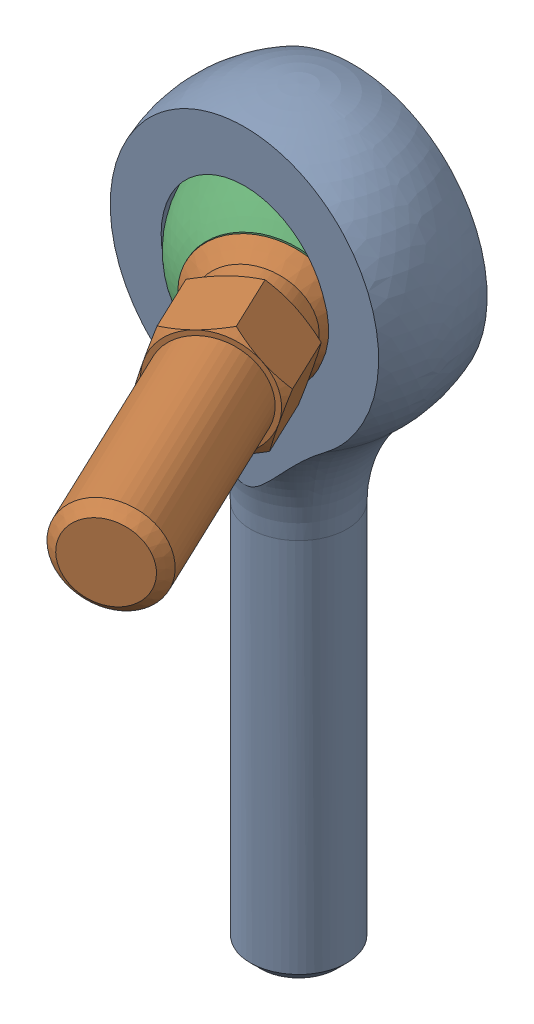
SolidWorks assembly 1_4-28 Oil-Embedded Ball Joint 6072K11, configuration Default. Lengths in mm.
Overall size (29.34 49.21 34.6).
2 component instances, 2 part files, 2 mates.
Components (placement in the parent):
- 1_4-28 Oil-Embedded Ball Joint L 6072K11-1: 1_4-28 Oil-Embedded Ball Joint L 6072K11 [6072K11] at origin size (19.05 49.21 7.14)
- 1_4-28 Oil-Embedded Ball Joint U 6072K11-1: 1_4-28 Oil-Embedded Ball Joint U 6072K11 [6072K11] at (-8.8328 24.6716 4.2761) x (-0.662864 -0.686715 0.298385) z (0.422389 -0.013918 0.906308) size (12.7 12.7 30.95)
Mates (geometry in assembly coordinates):
- Concentric1: concentric: sphere of 1_4-28 Oil-Embedded Ball Joint L 6072K11-1; sphere of 1_4-28 Oil-Embedded Ball Joint U 6072K11-1
- LimitAngle1: limit planar angle = 0.436332 rad aligned: line of 1_4-28 Oil-Embedded Ball Joint U 6072K11-1 through (-3.4854 14.4023 -7.4786) axis (0.422389 -0.013918 0.906308)
